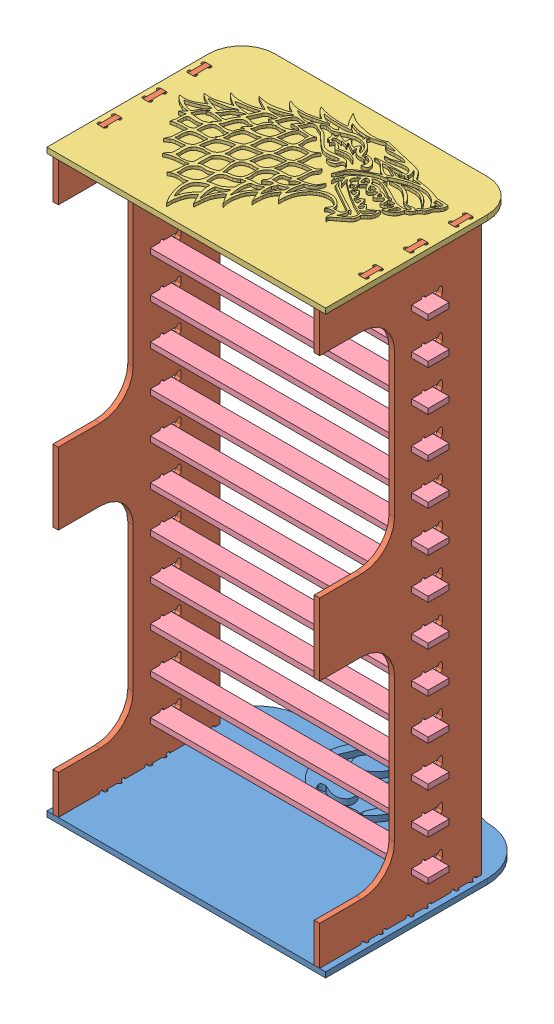
SolidWorks assembly Assem1, configuration Default. Lengths in mm.
Overall size (1000 1946 789.51).
17 component instances, 4 part files, 16 mates.
Components (placement in the parent):
- 1-front-1: 1-front [Default] at (443.817 7.0876 388.209) size (930 38 789.51)
- side-1: side [Default] at (-448.183 25.0876 388.209) x (0 1 0) z (0 0 1) size (1936 18 540)
- side-2: side [Default] at (423.817 25.0876 388.209) x (0 1 0) z (0 0 1) size (1936 18 540)
- back-1: back [Default] at (443.817 1925.0876 388.209) size (930 28 650)
- link-1: link [Default] at (478.817 141.9657 81.0848) size (1000 18 70)
- link-2: link [Default] at (478.817 277.6757 81.0848) size (1000 18 70)
- link-3: link [Default] at (478.817 413.3857 81.0848) size (1000 18 70)
- link-4: link [Default] at (478.817 549.0957 81.0848) size (1000 18 70)
- link-5: link [Default] at (478.817 684.8057 81.0848) size (1000 18 70)
- link-6: link [Default] at (478.817 820.5157 81.0848) size (1000 18 70)
- link-7: link [Default] at (478.817 956.2257 81.0848) size (1000 18 70)
- link-8: link [Default] at (478.817 1091.9357 81.0848) size (1000 18 70)
- link-9: link [Default] at (478.817 1227.6457 81.0848) size (1000 18 70)
- link-10: link [Default] at (478.817 1363.3557 81.0848) size (1000 18 70)
- link-11: link [Default] at (478.817 1499.0657 81.0848) size (1000 18 70)
- link-12: link [Default] at (478.817 1634.7757 81.0848) size (1000 18 70)
- link-13: link [Default] at (478.817 1770.4857 81.0848) size (1000 18 70)
Mates (geometry in assembly coordinates):
- Coincident5: coincident aligned: plane of 1-front-1 through (443.817 7.0876 388.209) normal (0 -1 0); plane of side-1 through (-466.183 7.0876 388.209) normal (0 -1 0)
- Coincident6: coincident aligned: line of 1-front-1 through (-448.183 7.0876 -74.491) axis (0 0 -1); line of side-1 through (-448.183 7.0876 -61.791) axis (0 0 -1)
- Coincident7: coincident aligned: line of 1-front-1 through (-466.183 7.0876 -121.791) axis (1 0 0); line of side-1 through (-466.183 7.0876 -121.791) axis (1 0 0)
- Coincident8: coincident aligned: plane of 1-front-1 through (443.817 7.0876 388.209) normal (0 -1 0); plane of side-2 through (405.817 7.0876 388.209) normal (0 -1 0)
- Coincident9: coincident: moEndPointRef_w of 1-front-1; moEndPointRef_w of side-2
- Coincident10: coincident aligned: line of 1-front-1 through (423.817 7.0876 -74.491) axis (0 0 -1); line of side-2 through (423.817 7.0876 -61.791) axis (0 0 -1)
- Coincident11: coincident aligned: plane of side-1 through (-466.183 1943.0876 388.209) normal (0 1 0); plane of back-1 through (443.817 1943.0876 388.209) normal (0 1 0)
- Coincident12: coincident aligned: line of side-1 through (-466.183 1943.0876 -61.791) axis (0 0 -1); line of back-1 through (-466.183 1943.0876 -74.491) axis (0 0 -1)
- Coincident13: coincident aligned: line of side-1 through (-466.183 1943.0876 -121.791) axis (1 0 0); line of back-1 through (-466.183 1943.0876 -121.791) axis (1 0 0)
- Coincident18: coincident anti-aligned: plane of side-2 through (405.817 25.0876 388.209) normal (-1 0 0); plane of link-1 through (405.817 159.9657 81.0848) normal (1 0 0)
- Coincident20: coincident anti-aligned: plane of side-2 through (405.817 25.0876 49.0848) normal (0 0 -1); plane of link-1 through (423.817 159.9657 49.0848) normal (0 0 1)
- Parallel4: parallel aligned: line of side-2 through (423.817 141.9657 36.3848) axis (0 0 -1); line of link-1 through (478.817 141.9657 81.0848) axis (0 0 -1)
- Coincident22: coincident anti-aligned: plane of side-2 through (405.817 141.9657 388.209) normal (0 1 0); plane of link-1 through (478.817 141.9657 81.0848) normal (0 -1 0)
- Coincident23: coincident anti-aligned: plane of side-1 through (-466.183 295.6757 388.209) normal (0 -1 0); plane of link-2 through (478.817 295.6757 81.0848) normal (0 1 0)
- Coincident24: coincident aligned: line of side-1 through (-466.183 277.6757 49.0848) axis (1 0 0); line of link-2 through (-466.183 277.6757 49.0848) axis (1 0 0)
- Coincident25: coincident anti-aligned: plane of side-1 through (-466.183 25.0876 388.209) normal (-1 0 0); plane of link-2 through (-466.183 295.6757 81.0848) normal (1 0 0)
